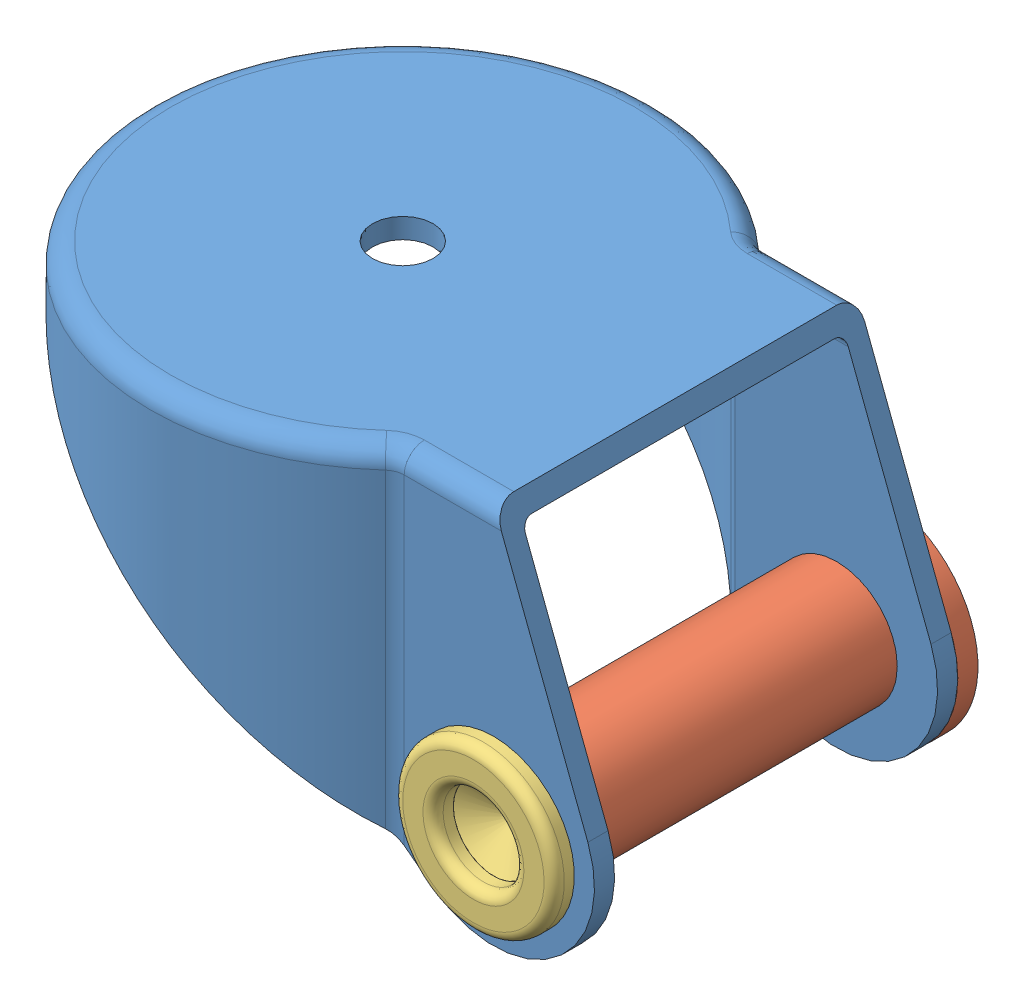
SolidWorks assembly B - Chape, configuration Défaut. Lengths in mm.
Overall size (31 19 25).
3 component instances, 3 part files, 4 mates.
Components (placement in the parent):
- Chape-1: Chape [Défaut] at (11.8446 -6.1032 31) size (31 19 25)
- Rivet2 A-1: Rivet2 A [Défaut] at (11.8446 -6.1032 22) size (10 10 19.48)
- Rivet2 B-1: Rivet2 B [Défaut] at (11.8446 -6.1032 40) x (0 0 -1) z (0.975007 0.222176 0) size (14 8 8)
Mates (geometry in assembly coordinates):
- Coaxiale1: concentric aligned: cylinder of Chape-1 through (11.8446 -6.1032 22) axis (0 0 1) radius 3; cylinder of Rivet2 B-1 through (11.8446 -6.1032 48.5376) axis (0 0 1) radius 3
- Coïncidente1: coincident anti-aligned: plane of Chape-1 through (-14.1554 -11.1032 40) normal (0 0 1); plane of Rivet2 B-1 through (11.1781 -3.1781 40) normal (0 0 -1)
- Coaxiale2: concentric aligned: cylinder of Chape-1 through (11.8446 -6.1032 22) axis (0 0 1) radius 3; cylinder of Rivet2 A-1 through (11.8446 -6.1032 49.6552) axis (0 0 1) radius 3
- Coïncidente2: coincident anti-aligned: plane of Chape-1 through (-14.1554 7.8968 22) normal (0 0 -1); plane of Rivet2 A-1 through (11.8446 -3.1032 22) normal (0 0 1)
